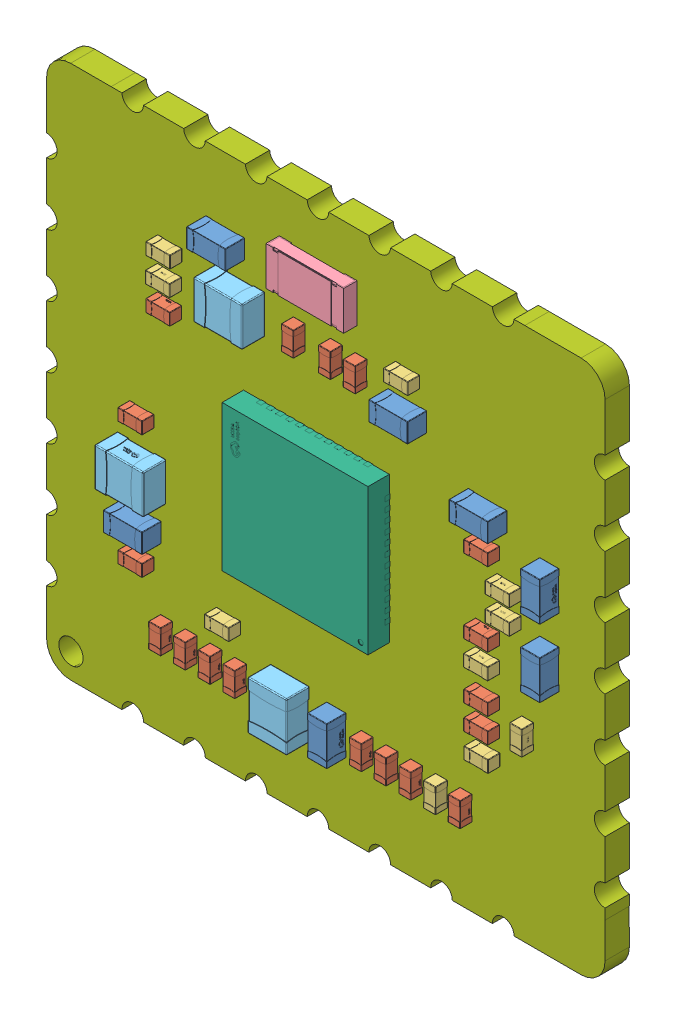
SolidWorks assembly 3D_邮票孔模块_2023-03-31.step, configuration 默认. Lengths in mm.
Overall size (22.97 21.97 1.95).
121 component instances, 7 part files, 0 mates.
Components (placement in the parent):
- C1.step-1: C1.step [默认] at (-3.81 8.001 1) x (-1 0 0) z (0 0 1) size (1.6 0.8 0.8)
  - C0603.step-1: C0603.step [默认] at origin size (1.6 0.8 0.8)
    - SOLID.step-1: SOLID.step [默认] at origin size (1.6 0.8 0.8)
- C11.step-1: C11.step [默认] at (-7.239 -3.81 1) x (-1 0 0) z (0 0 1) size (1.6 0.8 0.8)
  - C0603.step-1: C0603.step [默认] at origin size (1.6 0.8 0.8)
    - SOLID.step-1: SOLID.step [默认] at origin size (1.6 0.8 0.8)
- C12.step-1: C12.step [默认] at (3.683 5.588 1) x (-1 0 0) z (0 0 1) size (1.6 0.8 0.8)
  - C0603.step-1: C0603.step [默认] at origin size (1.6 0.8 0.8)
    - SOLID.step-1: SOLID.step [默认] at origin size (1.6 0.8 0.8)
- C14.step-1: C14.step [默认] at (6.985 3.683 1) x (-1 0 0) z (0 0 1) size (1.6 0.8 0.8)
  - C0603.step-1: C0603.step [默认] at origin size (1.6 0.8 0.8)
    - SOLID.step-1: SOLID.step [默认] at origin size (1.6 0.8 0.8)
- C15.step-1: C15.step [默认] at (9.525 2.286 1) x (0 -1 0) z (0 0 1) size (1.6 0.8 0.8)
  - C0603.step-1: C0603.step [默认] at origin size (1.6 0.8 0.8)
    - SOLID.step-1: SOLID.step [默认] at origin size (1.6 0.8 0.8)
- C16.step-1: C16.step [默认] at (9.525 -0.508 1) x (0 1 0) z (0 0 1) size (1.6 0.8 0.8)
  - C0603.step-1: C0603.step [默认] at origin size (1.6 0.8 0.8)
    - SOLID.step-1: SOLID.step [默认] at origin size (1.6 0.8 0.8)
- C18.step-1: C18.step [默认] at (0.762 -7.239 1) x (0 -1 0) z (0 0 1) size (1.6 0.8 0.8)
  - C0603.step-1: C0603.step [默认] at origin size (1.6 0.8 0.8)
    - SOLID.step-1: SOLID.step [默认] at origin size (1.6 0.8 0.8)
- C2.step-1: C2.step [默认] at (2.032 -7.239 1) x (0 -1 0) z (0 0 1) size (1 0.5 0.5)
  - C0402.step-1: C0402.step [默认] at origin size (1 0.5 0.5)
    - SOLID-0.step-1: SOLID-0.step [默认] at origin size (1 0.5 0.5)
- C3.step-1: C3.step [默认] at (-3.175 -7.239 1) x (0 -1 0) z (0 0 1) size (1 0.5 0.5)
  - C0402.step-1: C0402.step [默认] at origin size (1 0.5 0.5)
    - SOLID-0.step-1: SOLID-0.step [默认] at origin size (1 0.5 0.5)
- C4.step-1: C4.step [默认] at (-4.191 -7.239 1) x (0 -1 0) z (0 0 1) size (1 0.5 0.5)
  - C0402.step-1: C0402.step [默认] at origin size (1 0.5 0.5)
    - SOLID-0.step-1: SOLID-0.step [默认] at origin size (1 0.5 0.5)
- C5.step-1: C5.step [默认] at (6.985 -0.635 1) size (1 0.5 0.5)
  - C0402.step-1: C0402.step [默认] at origin size (1 0.5 0.5)
    - SOLID-0.step-1: SOLID-0.step [默认] at origin size (1 0.5 0.5)
- C6.step-1: C6.step [默认] at (-5.207 -7.239 1) x (0 -1 0) z (0 0 1) size (1 0.5 0.5)
  - C0402.step-1: C0402.step [默认] at origin size (1 0.5 0.5)
    - SOLID-0.step-1: SOLID-0.step [默认] at origin size (1 0.5 0.5)
- C7.step-1: C7.step [默认] at (4.064 -7.239 1) x (0 -1 0) z (0 0 1) size (1 0.5 0.5)
  - C0402.step-1: C0402.step [默认] at origin size (1 0.5 0.5)
    - SOLID-0.step-1: SOLID-0.step [默认] at origin size (1 0.5 0.5)
- C8.step-1: C8.step [默认] at (0.762 6.096 1) x (0 1 0) z (0 0 1) size (1 0.5 0.5)
  - C0402.step-1: C0402.step [默认] at origin size (1 0.5 0.5)
    - SOLID-0.step-1: SOLID-0.step [默认] at origin size (1 0.5 0.5)
- C9.step-1: C9.step [默认] at (-0.762 6.096 1) x (0 1 0) z (0 0 1) size (1 0.5 0.5)
  - C0402.step-1: C0402.step [默认] at origin size (1 0.5 0.5)
    - SOLID-0.step-1: SOLID-0.step [默认] at origin size (1 0.5 0.5)
- C13.step-1: C13.step [默认] at (6.985 2.413 1) x (-1 0 0) z (0 0 1) size (1 0.5 0.5)
  - C0402.step-1: C0402.step [默认] at origin size (1 0.5 0.5)
    - SOLID-0.step-1: SOLID-0.step [默认] at origin size (1 0.5 0.5)
- C17.step-1: C17.step [默认] at (-7.239 -5.08 1) x (-1 0 0) z (0 0 1) size (1 0.5 0.5)
  - C0402.step-1: C0402.step [默认] at origin size (1 0.5 0.5)
    - SOLID-0.step-1: SOLID-0.step [默认] at origin size (1 0.5 0.5)
- C19.step-1: C19.step [默认] at (-7.239 0 1) x (-1 0 0) z (0 0 1) size (1 0.5 0.5)
  - C0402.step-1: C0402.step [默认] at origin size (1 0.5 0.5)
    - SOLID-0.step-1: SOLID-0.step [默认] at origin size (1 0.5 0.5)
- C20.step-1: C20.step [默认] at (6.985 -2.921 1) x (-1 0 0) z (0 0 1) size (1 0.5 0.5)
  - C0402.step-1: C0402.step [默认] at origin size (1 0.5 0.5)
    - SOLID-0.step-1: SOLID-0.step [默认] at origin size (1 0.5 0.5)
- C21.step-1: C21.step [默认] at (-6.096 4.445 1) size (1 0.5 0.5)
  - C0402.step-1: C0402.step [默认] at origin size (1 0.5 0.5)
    - SOLID-0.step-1: SOLID-0.step [默认] at origin size (1 0.5 0.5)
- C22.step-1: C22.step [默认] at (6.096 -7.239 1) x (0 -1 0) z (0 0 1) size (1 0.5 0.5)
  - C0402.step-1: C0402.step [默认] at origin size (1 0.5 0.5)
    - SOLID-0.step-1: SOLID-0.step [默认] at origin size (1 0.5 0.5)
- C23.step-1: C23.step [默认] at (6.985 -3.937 1) x (-1 0 0) z (0 0 1) size (1 0.5 0.5)
  - C0402.step-1: C0402.step [默认] at origin size (1 0.5 0.5)
    - SOLID-0.step-1: SOLID-0.step [默认] at origin size (1 0.5 0.5)
- C24.step-1: C24.step [默认] at (3.048 -7.239 1) x (0 1 0) z (0 0 1) size (1 0.5 0.5)
  - C0402.step-1: C0402.step [默认] at origin size (1 0.5 0.5)
    - SOLID-0.step-1: SOLID-0.step [默认] at origin size (1 0.5 0.5)
- C25.step-1: C25.step [默认] at (-6.223 -7.239 1) x (0 -1 0) z (0 0 1) size (1 0.5 0.5)
  - C0402.step-1: C0402.step [默认] at origin size (1 0.5 0.5)
    - SOLID-0.step-1: SOLID-0.step [默认] at origin size (1 0.5 0.5)
- C26.step-1: C26.step [默认] at (1.778 6.096 1) x (0 1 0) z (0 0 1) size (1 0.5 0.5)
  - C0402.step-1: C0402.step [默认] at origin size (1 0.5 0.5)
    - SOLID-0.step-1: SOLID-0.step [默认] at origin size (1 0.5 0.5)
- C10.step-1: C10.step [默认] at (3.683 6.858 1) x (-1 0 0) z (0 0 1) size (1 0.5 0.5)
  - R0402.step-1: R0402.step [默认] at origin size (1 0.5 0.5)
    - SOLID-1.step-1: SOLID-1.step [默认] at origin size (1 0.5 0.5)
- R2.step-1: R2.step [默认] at (6.985 -1.651 1) size (1 0.5 0.5)
  - R0402.step-1: R0402.step [默认] at origin size (1 0.5 0.5)
    - SOLID-1.step-1: SOLID-1.step [默认] at origin size (1 0.5 0.5)
- R4.step-1: R4.step [默认] at (7.874 1.397 1) size (1 0.5 0.5)
  - R0402.step-1: R0402.step [默认] at origin size (1 0.5 0.5)
    - SOLID-1.step-1: SOLID-1.step [默认] at origin size (1 0.5 0.5)
- R5.step-1: R5.step [默认] at (-3.683 -5.588 1) x (-1 0 0) z (0 0 1) size (1 0.5 0.5)
  - R0402.step-1: R0402.step [默认] at origin size (1 0.5 0.5)
    - SOLID-1.step-1: SOLID-1.step [默认] at origin size (1 0.5 0.5)
- R6.step-1: R6.step [默认] at (7.874 0.381 1) size (1 0.5 0.5)
  - R0402.step-1: R0402.step [默认] at origin size (1 0.5 0.5)
    - SOLID-1.step-1: SOLID-1.step [默认] at origin size (1 0.5 0.5)
- R8.step-1: R8.step [默认] at (6.985 -4.953 1) x (-1 0 0) z (0 0 1) size (1 0.5 0.5)
  - R0402.step-1: R0402.step [默认] at origin size (1 0.5 0.5)
    - SOLID-1.step-1: SOLID-1.step [默认] at origin size (1 0.5 0.5)
- R10.step-1: R10.step [默认] at (-6.096 5.461 1) size (1 0.5 0.5)
  - R0402.step-1: R0402.step [默认] at origin size (1 0.5 0.5)
    - SOLID-1.step-1: SOLID-1.step [默认] at origin size (1 0.5 0.5)
- R11.step-1: R11.step [默认] at (5.08 -7.239 1) x (0 1 0) z (0 0 1) size (1 0.5 0.5)
  - R0402.step-1: R0402.step [默认] at origin size (1 0.5 0.5)
    - SOLID-1.step-1: SOLID-1.step [默认] at origin size (1 0.5 0.5)
- R12.step-1: R12.step [默认] at (8.636 -3.429 1) x (0 -1 0) z (0 0 1) size (1 0.5 0.5)
  - R0402.step-1: R0402.step [默认] at origin size (1 0.5 0.5)
    - SOLID-1.step-1: SOLID-1.step [默认] at origin size (1 0.5 0.5)
- R24.step-1: R24.step [默认] at (-6.096 6.477 1) x (-1 0 0) z (0 0 1) size (1 0.5 0.5)
  - R0402.step-1: R0402.step [默认] at origin size (1 0.5 0.5)
    - SOLID-1.step-1: SOLID-1.step [默认] at origin size (1 0.5 0.5)
- R17.step-1: R17.step [默认] at (0 8.382 1) x (-1 0 0) z (0 0 1) size (3.2 1.6 0.56)
  - R1206.step-1: R1206.step [默认] at origin size (3.2 1.6 0.56)
    - COMPOUND.step-1: COMPOUND.step [默认] at origin size (3.2 1.6 0.56)
- L1.step-1: L1.step [默认] at (-3.175 6.096 1) x (-1 0 0) z (0 0 1) size (2 1.6 0.95)
  - L0806.step-1: L0806.step [默认] at origin size (2 1.6 0.95)
    - SOLID-2.step-1: SOLID-2.step [默认] at origin size (2 1.6 0.95)
- L2.step-1: L2.step [默认] at (-7.239 -1.905 1) size (2 1.6 0.95)
  - L0806.step-1: L0806.step [默认] at origin size (2 1.6 0.95)
    - SOLID-2.step-1: SOLID-2.step [默认] at origin size (2 1.6 0.95)
- L3.step-1: L3.step [默认] at (-1.143 -7.239 1) x (0 1 0) z (0 0 1) size (2 1.6 0.95)
  - L0806.step-1: L0806.step [默认] at origin size (2 1.6 0.95)
    - SOLID-2.step-1: SOLID-2.step [默认] at origin size (2 1.6 0.95)
- U1.step-1: U1.step [默认] at (0 0 1) size (6 6 0.93)
  - AXP202.step-1: AXP202.step [默认] at origin size (6 6 0.93)
    - COMPOUND-3.step-1: COMPOUND-3.step [默认] at origin size (6 6 0.93)
- COMPOUND-4.step-1: COMPOUND-4.step [默认] at origin size (22.97 21.97 1)
